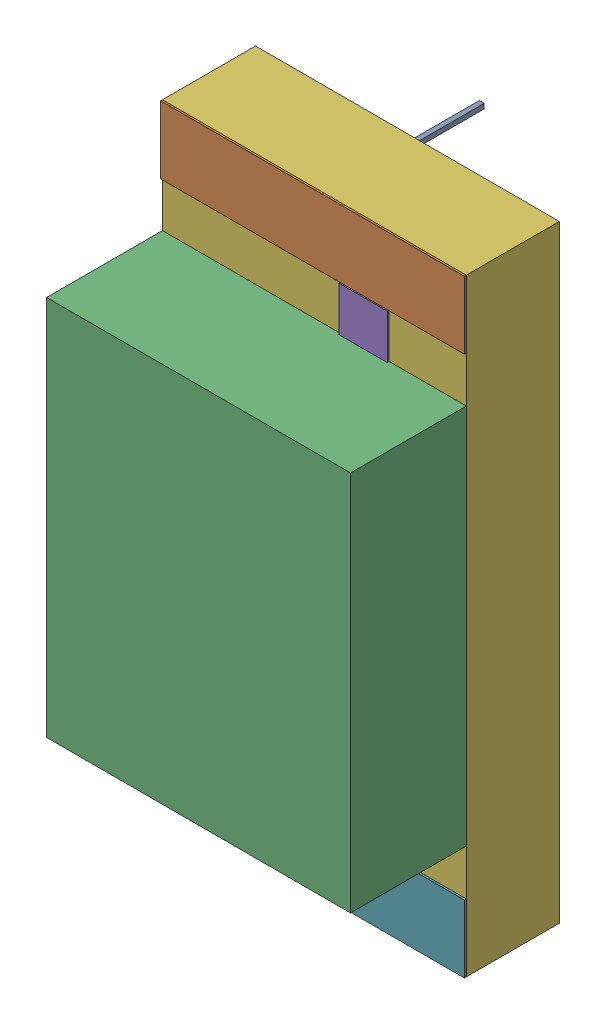
SolidWorks assembly Ddebug2, configuration Défaut. Lengths in mm.
Overall size (1.6 3.2 1.52).
15 component instances, 6 part files, 0 mates.
Components (placement in the parent):
- SW3dPS-LED1206Y-1: SW3dPS-LED1206Y [Défaut] at (37.6554 30.7341 0) x (0 -1 0) z (0 0 1) size (3.2 1.6 1.52)
  - SW3dPS-LED1206Y_Board-1: SW3dPS-LED1206Y_Board [Défaut] at (0 0 -0.4039) size (0.03 0.03 0.42)
  - SW3dPS-LED1206Y_Open_CASCADE_STEP_translator_6.2_294.2-1: SW3dPS-LED1206Y_Open_CASCADE_STEP_translator_6.2_294.2 [Défaut] at origin size (3.2 1.6 1.1)
    - SW3dPS-LED1206Y_352697808-1: SW3dPS-LED1206Y_352697808 [Défaut] at (0.1016 0.0127 0.5027) size (0.36 1.6 0.01)
      - SW3dPS-LED1206Y_Extruded2-1: SW3dPS-LED1206Y_Extruded2 [Défaut] at origin size (0.36 1.6 0.01)
    - SW3dPS-LED1206Y_352697680-1: SW3dPS-LED1206Y_352697680 [Défaut] at (1.524 0.0127 0.5027) size (2.01 1.6 0.61)
      - SW3dPS-LED1206Y_Extruded4-1: SW3dPS-LED1206Y_Extruded4 [Défaut] at origin size (2.01 1.6 0.61)
    - SW3dPS-LED1206Y_352698192-1: SW3dPS-LED1206Y_352698192 [Défaut] at (2.1971 0.0254 0.5027) size (1.14 0.76 0.01)
      - SW3dPS-LED1206Y_Extruded3-1: SW3dPS-LED1206Y_Extruded3 [Défaut] at origin size (1.14 0.76 0.01)
    - SW3dPS-LED1206Y_352699472-1: SW3dPS-LED1206Y_352699472 [Défaut] at (0.6096 0.0254 0.5027) size (0.65 0.76 0.01)
      - SW3dPS-LED1206Y_Extruded-1: SW3dPS-LED1206Y_Extruded [Défaut] at origin size (0.65 0.76 0.01)
    - SW3dPS-LED1206Y_352697936-1: SW3dPS-LED1206Y_352697936 [Défaut] at (1.524 0.0127 0.0127) size (3.2 1.6 0.49)
      - SW3dPS-LED1206Y_Extruded1-1: SW3dPS-LED1206Y_Extruded1 [Défaut] at origin size (3.2 1.6 0.49)
    - SW3dPS-LED1206Y_352697808-2: SW3dPS-LED1206Y_352697808 [Défaut] at (2.9464 0.0127 0.5027) size (0.36 1.6 0.01)
      - SW3dPS-LED1206Y_Extruded2-1: SW3dPS-LED1206Y_Extruded2 [Défaut] at origin size (0.36 1.6 0.01)
